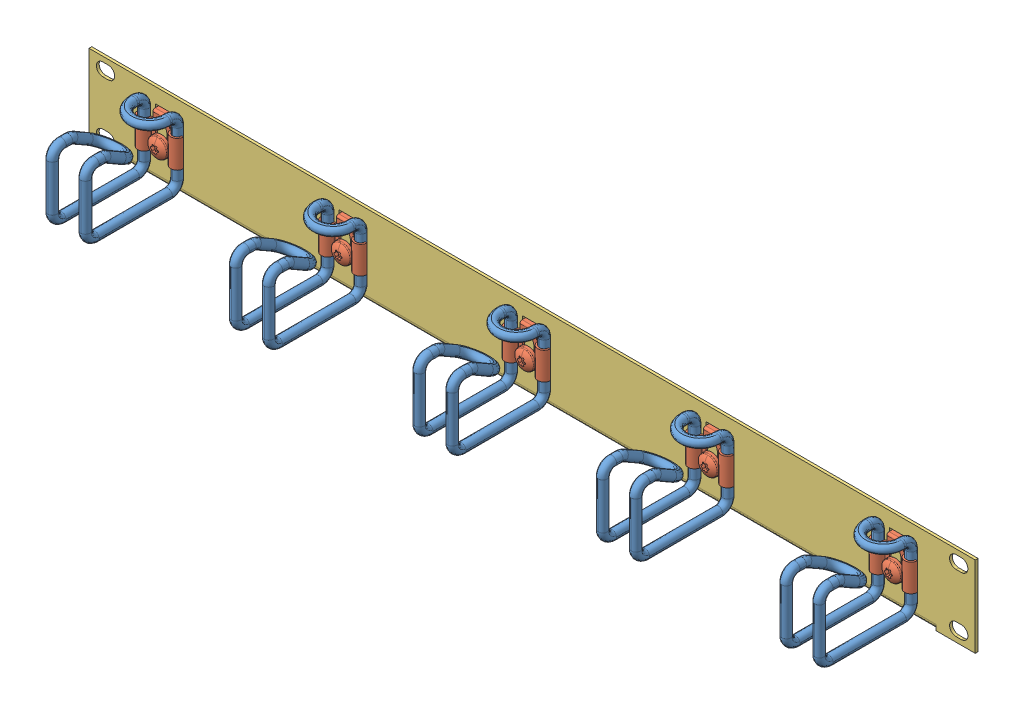
SolidWorks assembly 5502_205, configuration Default. Lengths in mm.
Overall size (483 44.1 78).
11 component instances, 3 part files, 0 mates.
Components (placement in the parent):
- 5502_205-hook-1: 5502_205-hook [Default] at (200 2.05 0) size (23 40 55)
- 5502_205-hook-2: 5502_205-hook [Default] at (100 2.05 0) size (23 40 55)
- 5502_205-hook-3: 5502_205-hook [Default] at (0 2.05 0) size (23 40 55)
- 5502_205-hook-4: 5502_205-hook [Default] at (-100 2.05 0) size (23 40 55)
- 5502_205-hook-5: 5502_205-hook [Default] at (-200 2.05 0) size (23 40 55)
- 5502_205-holder-1: 5502_205-holder [Default] at (200 15.5 1.2) size (25 20.4 16.8)
- 5502_205-holder-2: 5502_205-holder [Default] at (100 15.5 1.2) size (25 20.4 16.8)
- 5502_205-holder-3: 5502_205-holder [Default] at (0 15.5 1.2) size (25 20.4 16.8)
- 5502_205-holder-4: 5502_205-holder [Default] at (-100 15.5 1.2) size (25 20.4 16.8)
- 5502_205-holder-5: 5502_205-holder [Default] at (-200 15.5 1.2) size (25 20.4 16.8)
- 5502_205-pannel-1: 5502_205-pannel [Default] at origin size (483 44.1 23)
